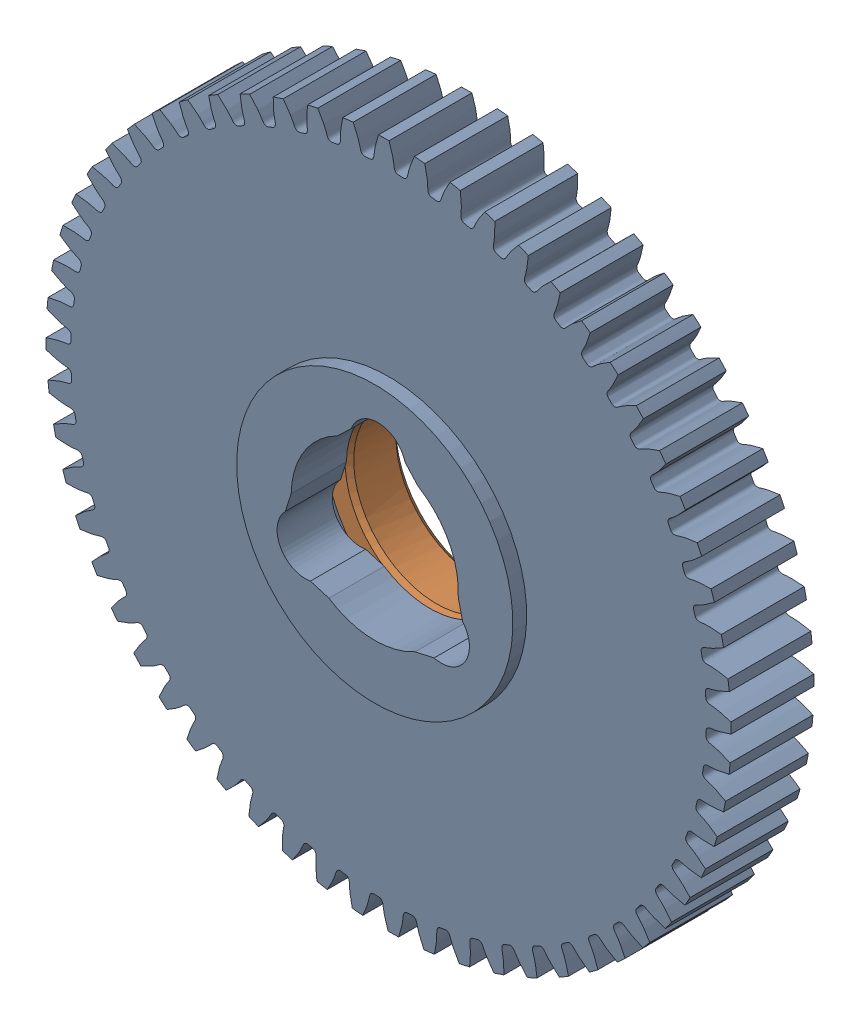
SolidWorks assembly 217-2713-101 Rev1, configuration Default. Lengths in mm.
Overall size (81.88 81.88 12.7).
2 component instances, 2 part files, 0 mates.
Components (placement in the parent):
- 217-2713-001_60t Steel-1: 217-2713-001_60t Steel [Default] at (0 0 3.302) x (0.999266 -0.038302 0) z (0 0 1) size (78.91 78.91 11.11)
- 217-2428-022 Rev1-1: 217-2428-022 Rev1 [Default] at origin size (28.57 28.57 6.1)
